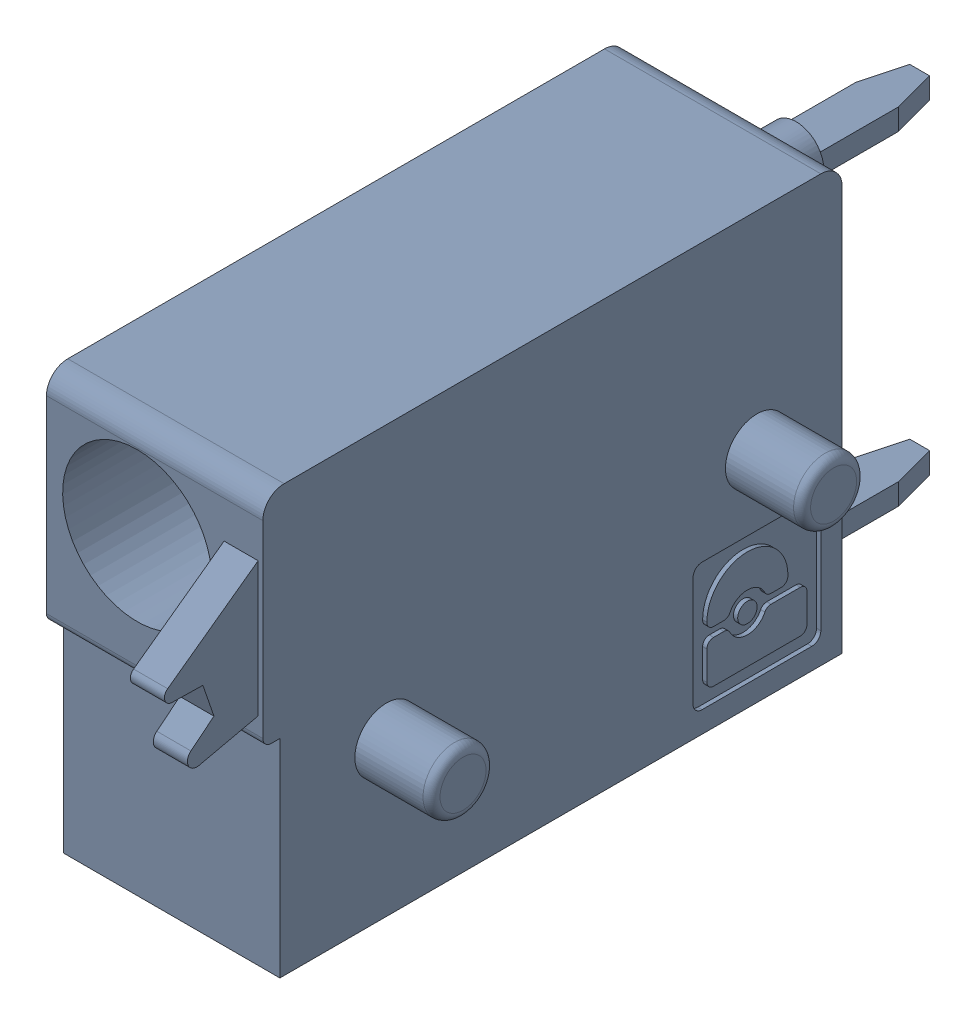
SolidWorks assembly J5, configuration Default. Lengths in mm.
Overall size (6.88 10 19.2).
2 component instances, 1 part files, 0 mates.
Components (placement in the parent):
- 1790348-1: 1790348 [Default] at (9.5251 -7.6199 0) x (0 1 0) z (1 0 0) size (10 19.2 6.88)
  - ffkds-v2-5.08-1: ffkds-v2-5.08 [Default] at (-23.7414 -38.158 -2.54) x (0 -1 0) z (0 0 1) size (19.2 10 6.88)
